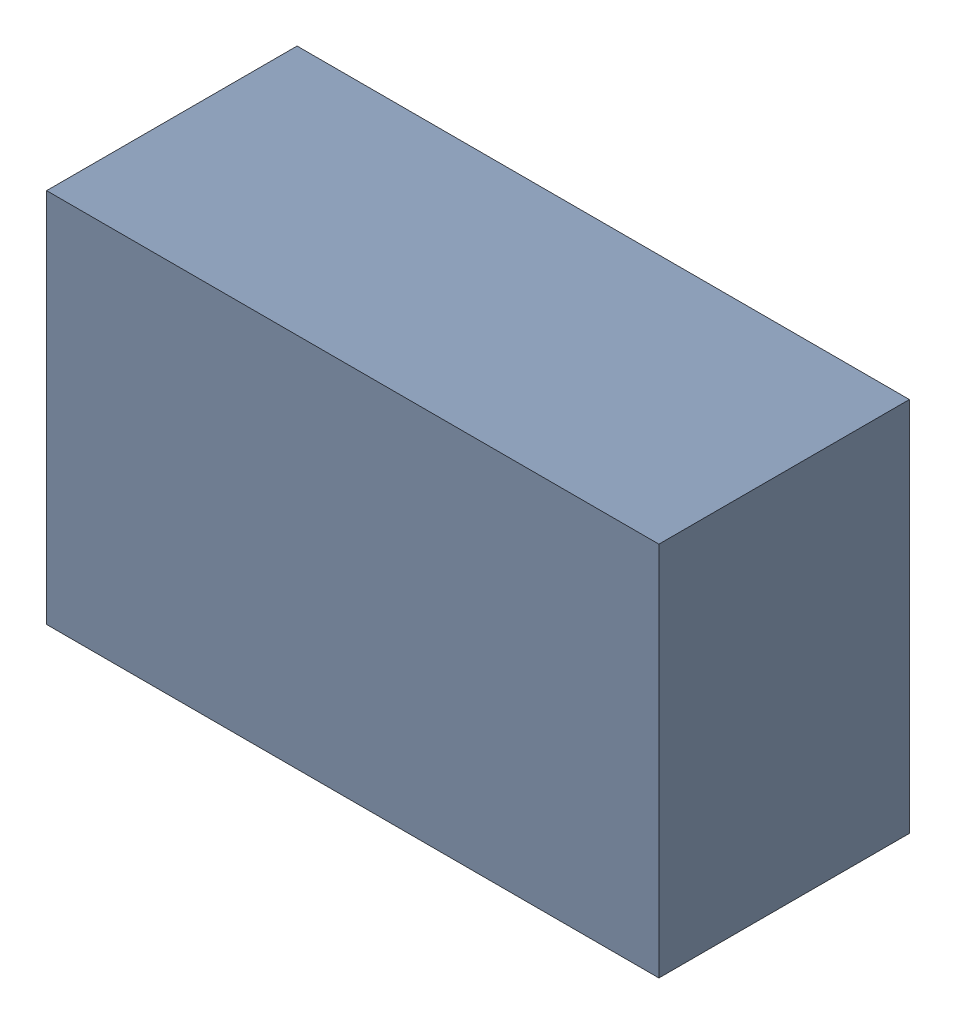
SolidWorks assembly Q301_1PCB, configuration Default. Lengths in mm.
Overall size (2.2 1.35 0.9).
2 component instances, 1 part files, 0 mates.
Components (placement in the parent):
- 846486960-1: 846486960 [Default] at (145.2 111.6 0.1) size (2.2 1.35 0.9)
  - Extruded_33-1: Extruded_33 [Default] at origin size (2.2 1.35 0.9)
